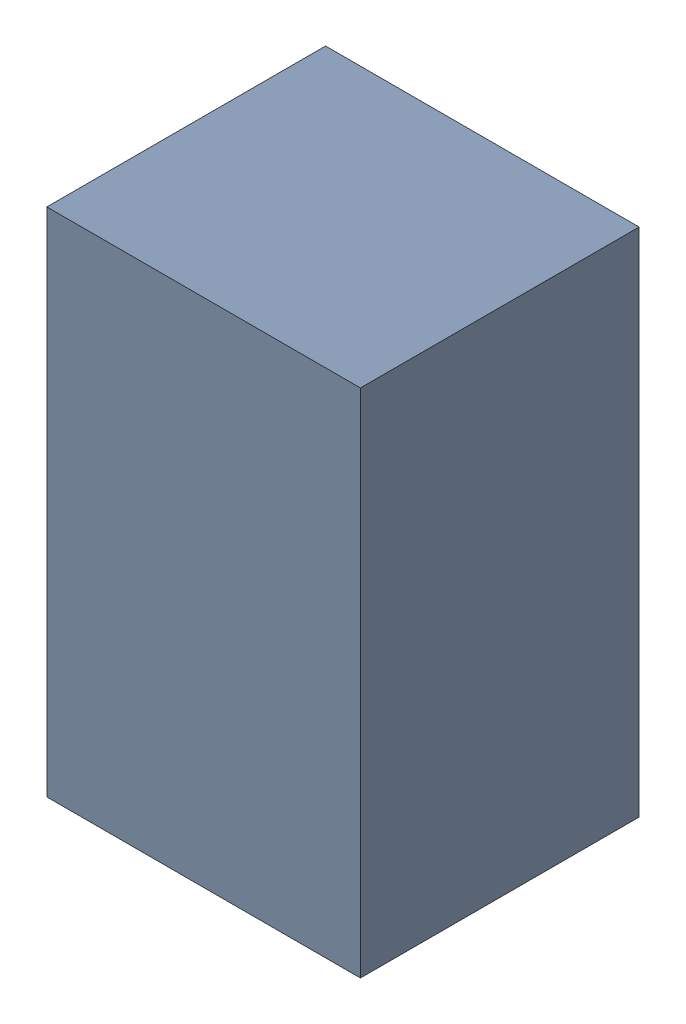
SolidWorks assembly C9, configuration Default. Lengths in mm.
Overall size (1.35 2.2 1.2).
2 component instances, 1 part files, 0 mates.
Components (placement in the parent):
- 407985568-1: 407985568 [Default] at (25.654 24.638 0.0127) size (1.35 2.2 1.2)
  - Extruded_3-1: Extruded_3 [Default] at origin size (1.35 2.2 1.2)
